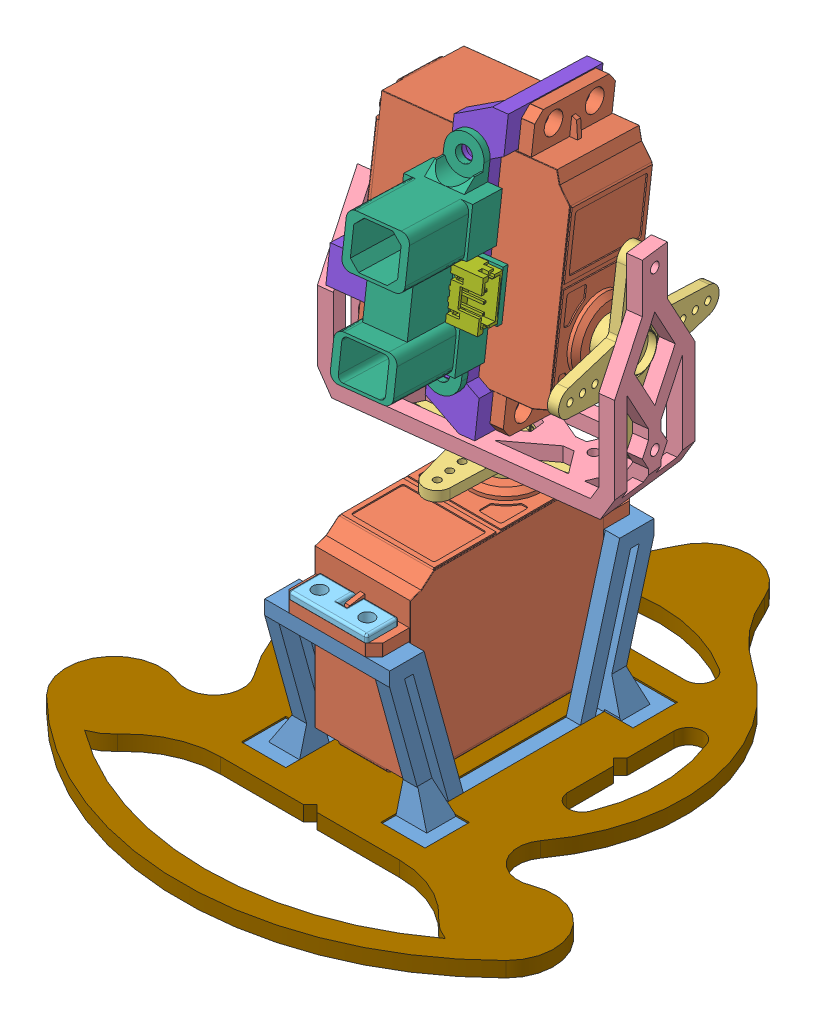
SolidWorks assembly 3D_scanner, configuration Default. Lengths in mm.
Overall size (102.2 115.45 119.22).
13 component instances, 9 part files, 30 mates.
Components (placement in the parent):
- pan_servo_housing-2: pan_servo_housing [Default] at (-13.4584 5.3983 50.9565) size (38.2 32.85 55.4)
- servo-2: servo [Default] at (-3.4584 11.7483 71.2565) x (0 1 0) z (-1 0 0) size (43 55.4 20)
- cross_horn-1: cross_horn [Default] at (-13.4584 54.7483 41.1565) x (0.120329 0 0.992734) z (-0.992734 0 0.120329) size (38.6 7.1 38.6)
- tilt_servo_mount-1: tilt_servo_mount [Default] at (-13.4584 59.8483 41.1565) x (0.992734 0 -0.120329) z (0.120329 0 0.992734) size (56 44.55 19.28)
- servo-3: servo [Default] at (-32.7508 113.0859 49.0326) x (0.992734 0 -0.120329) z (-0.119039 -0.146024 -0.982093) size (43 55.4 20)
- cross_horn-2: cross_horn [Default] at (9.2752 81.8483 38.4009) x (0.120329 0 0.992734) z (0 1 0) size (38.6 7.1 38.6)
- gasket-1: gasket [Default] at (-13.4584 40.7483 26.6565) size (16.5 3 6.75)
- gasket-2: gasket [Default] at (-13.4584 40.7483 75.2565) x (-1 0 0) z (0 0 -1) size (16.5 3 6.75)
- ir_distance_sensor-1: ir_distance_sensor [Default] at (7.9607 77.6988 24.7243) x (-0.017571 0.989281 -0.144963) z (0.119039 0.146024 0.982093) size (44.5 17.75 21.6)
  - ir_distance_sensor_body-1: ir_distance_sensor_body [Default] at (12.3744 23.2408 27.1941) size (44.5 17.75 21.6)
  - 3-pin_JST_female-1: 3-pin_JST_female [Default] at (12.3744 11.9908 31.6941) x (1 0 0) z (0 -1 0) size (9.9 4.8 8.6)
- distance_sensor_mount-1: distance_sensor_mount [Default] at (-12.4109 93.5872 49.4664) x (0.992734 0 -0.120329) z (0.119039 0.146024 0.982093) size (35.56 55.39 23)
- alignment_plate-2: alignment_plate [Default] at (-13.4584 5.3983 50.9565) x (-1 0 0) z (0 0 -1) size (102.2 3.17 119.22)
Mates (geometry in assembly coordinates):
- Coincident2: coincident: plane of pan_servo_housing-2 through (-0.3584 38.2483 30.4565) normal (0 1 0); plane of servo-2 through (-23.4584 38.2483 30.6565) normal (0 -1 0)
- Width1: width: plane of pan_servo_housing-2 through (-23.5584 5.3983 50.9565) normal (1 0 0); plane of pan_servo_housing-2 through (-3.3584 5.3983 50.9565) normal (-1 0 0); plane of servo-2 through (-23.4584 11.7483 71.2565) normal (-1 0 0); plane of servo-2 through (-3.4584 11.7483 71.2565) normal (1 0 0)
- Width2: width: plane of pan_servo_housing-2 through (-5.6584 38.2483 71.4565) normal (0 0 -1); plane of pan_servo_housing-2 through (-21.2584 38.2483 30.4565) normal (0 0 1); plane of servo-2 through (-23.4584 11.7483 71.2565) normal (0 0 1); plane of servo-2 through (-23.4584 11.7483 30.6565) normal (0 0 -1)
- Coincident3: coincident: plane of servo-2 through (-13.4584 54.7483 41.1565) normal (0 1 0); plane of cross_horn-1 through (2.9713 54.7483 39.165) normal (0 -1 0)
- Concentric1: concentric: cylinder of servo-2 through (-13.4584 54.7483 41.1565) axis (0 -1 0) radius 3; cylinder of cross_horn-1 through (-13.4584 50.3483 41.1565) axis (0 1 0) radius 3
- LimitAngle1: limit planar angle = 1.432721 rad: plane of cross_horn-1 through (-9.7936 57.2483 40.6472) normal (-0.137637 0 -0.990483); plane of servo-2 through (-23.4584 11.7483 71.2565) normal (-1 0 0); cylinder of servo-2 through (-13.4584 34.7483 41.1565) axis (0 1 0) radius 1.25
- Coincident4: coincident: plane of cross_horn-1 through (2.9713 56.8483 39.165) normal (0 1 0); plane of tilt_servo_mount-1 through (-13.4584 56.8483 41.1565) normal (0 -1 0)
- Concentric2: concentric: cylinder of cross_horn-1 through (2.9713 50.3473 39.165) axis (0 1 0) radius 0.75; cylinder of tilt_servo_mount-1 through (2.9713 56.8483 39.165) axis (0 1 0) radius 1.05
- Concentric3: concentric: cylinder of cross_horn-1 through (-29.8882 50.3473 43.1479) axis (0 1 0) radius 0.75; cylinder of tilt_servo_mount-1 through (-29.8882 56.8483 43.1479) axis (0 1 0) radius 1.05
- Coincident5: coincident: plane of servo-3 through (9.2752 81.8483 38.4009) normal (0.992734 0 -0.120329); plane of cross_horn-2 through (9.2752 65.2983 38.4009) normal (-0.992734 0 0.120329)
- Concentric4: concentric: cylinder of servo-3 through (9.2752 81.8483 38.4009) axis (-0.992734 0 0.120329) radius 3; cylinder of cross_horn-2 through (4.9072 81.8483 38.9304) axis (0.992734 0 -0.120329) radius 3
- LimitAngle2: limit planar angle = 1.441702 rad: plane of cross_horn-2 through (11.3119 81.7837 34.4275) normal (0.0021 -0.999848 0.017326); plane of servo-3 through (-32.7508 113.0859 49.0326) normal (0.119039 0.146024 0.982093); cylinder of servo-3 through (-10.5795 81.8483 40.8075) axis (0.992734 0 -0.120329) radius 1.25
- Coincident6: coincident: plane of tilt_servo_mount-1 through (11.3599 59.8483 38.1482) normal (-0.992734 0 0.120329); plane of cross_horn-2 through (11.3599 65.2983 38.1482) normal (0.992734 0 -0.120329)
- Concentric7: concentric: cylinder of tilt_servo_mount-1 through (11.3599 98.3983 38.1482) axis (0.992734 0 -0.120329) radius 1.05; cylinder of cross_horn-2 through (4.9062 98.3983 38.9305) axis (0.992734 0 -0.120329) radius 0.75
- Concentric8: concentric: cylinder of tilt_servo_mount-1 through (11.3599 65.2983 38.1482) axis (0.992734 0 -0.120329) radius 1.05; cylinder of cross_horn-2 through (4.9062 65.2983 38.9305) axis (0.992734 0 -0.120329) radius 0.75
- Coincident7: coincident: plane of servo-2 through (-23.4584 40.7483 30.6565) normal (0 1 0); plane of gasket-1 through (-13.4584 40.7483 26.6565) normal (0 -1 0)
- Concentric9: concentric: cylinder of servo-2 through (-8.4584 11.7473 26.6565) axis (0 1 0) radius 2.25; cylinder of gasket-1 through (-8.4584 42.2483 26.6565) axis (0 -1 0) radius 1.4225
- Concentric10: concentric: cylinder of servo-2 through (-18.4584 11.7473 26.6565) axis (0 1 0) radius 2.25; cylinder of gasket-1 through (-18.4584 42.2483 26.6565) axis (0 -1 0) radius 1.4225
- Coincident8: coincident: plane of servo-2 through (-23.4584 40.7483 71.2565) normal (0 1 0); plane of gasket-2 through (-13.4584 40.7483 75.2565) normal (0 -1 0)
- Concentric11: concentric: cylinder of servo-2 through (-18.4584 11.7473 75.2565) axis (0 1 0) radius 2.25; cylinder of gasket-2 through (-18.4584 42.2483 75.2565) axis (0 -1 0) radius 1.4225
- Concentric12: concentric: cylinder of servo-2 through (-8.4584 11.7473 75.2565) axis (0 1 0) radius 2.25; cylinder of gasket-2 through (-8.4584 42.2483 75.2565) axis (0 -1 0) radius 1.4225
- Coincident9: coincident: line of ir_distance_sensor-1/ir_distance_sensor_body-1 through (-11.0538 84.798 60.9947) axis (0.119039 0.146024 0.982093); line of assembly
- Parallel1: parallel: plane of servo-3 through (-35.1316 110.1654 29.3908) normal (-0.992734 0 0.120329); plane of ir_distance_sensor-1/ir_distance_sensor_body-1 through (-17.6871 94.9629 60.2874) normal (-0.992734 0 0.120329)
- Coincident12: coincident: plane of ir_distance_sensor-1/ir_distance_sensor_body-1 through (-12.0914 93.9115 52.4342) normal (-0.119039 -0.146024 -0.982093); plane of distance_sensor_mount-1 through (-12.0537 94.0253 52.4127) normal (0.119039 0.146024 0.982093)
- Coincident18: coincident: plane of servo-3 through (-32.7508 113.0859 49.0326) normal (0.119039 0.146024 0.982093); plane of distance_sensor_mount-1 through (-12.4109 93.5872 49.4664) normal (-0.119039 -0.146024 -0.982093)
- Distance2: distance = 0.2 mm: plane of servo-3 through (-8.8242 110.1654 26.2021) normal (-0.992734 0 0.120329); plane of distance_sensor_mount-1 through (-6.4148 120.8447 47.7415) normal (0.992734 0 -0.120329)
- Coincident15: coincident: plane of servo-3 through (-6.4724 117.4861 24.8285) normal (-0.017571 0.989281 -0.144963); plane of distance_sensor_mount-1 through (-9.3931 120.8447 48.1025) normal (-0.017571 0.989281 -0.144963)
- Coincident21: coincident: plane of pan_servo_housing-2 through (-0.3584 5.3983 50.9565) normal (0 -1 0); plane of alignment_plate-2 through (7.0916 5.3983 61.7065) normal (0 -1 0)
- Width6: width: plane of pan_servo_housing-2 through (-0.3584 5.3983 50.9565) normal (1 0 0); plane of pan_servo_housing-2 through (-26.5584 5.3983 50.9565) normal (-1 0 0); plane of alignment_plate-2 through (-26.7084 5.3973 68.1065) normal (1 0 0); plane of alignment_plate-2 through (-0.2084 5.3973 68.1065) normal (-1 0 0)
- Width7: width: plane of pan_servo_housing-2 through (-3.3584 8.3983 77.2565) normal (0 0 1); plane of pan_servo_housing-2 through (-3.3584 8.3983 24.6565) normal (0 0 -1); plane of alignment_plate-2 through (-3.5084 5.3973 77.4065) normal (0 0 -1); plane of alignment_plate-2 through (-3.5084 5.3973 24.5065) normal (0 0 1)
